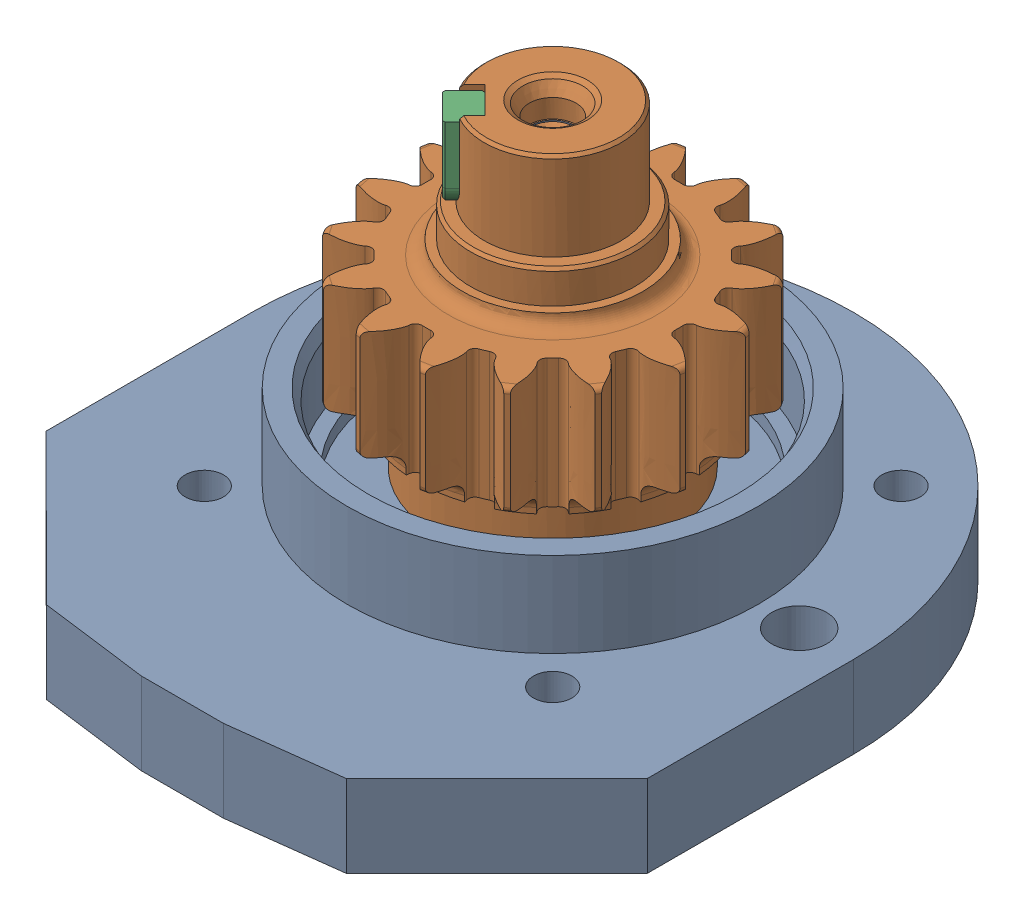
SolidWorks assembly g1_3_1_1_2, configuration 默认. Lengths in mm.
Overall size (219.6 152 245).
3 component instances, 3 part files, 0 mates.
Components (placement in the parent):
- g1_3_1_1_2-1-1: g1_3_1_1_2-1 [默认] at origin size (219.6 61 245)
- g1_3_1_1_2-2-1: g1_3_1_1_2-2 [默认] at (0 152 0) x (-0.047609 0 0.998866) z (0 1 0) size (120.16 120.16 117)
- g1_3_1_1_2-3-1: g1_3_1_1_2-3 [默认] at (-20.1525 129 20.1525) x (0 -1 0) z (0.707107 0 0.707107) size (28 11 14)
